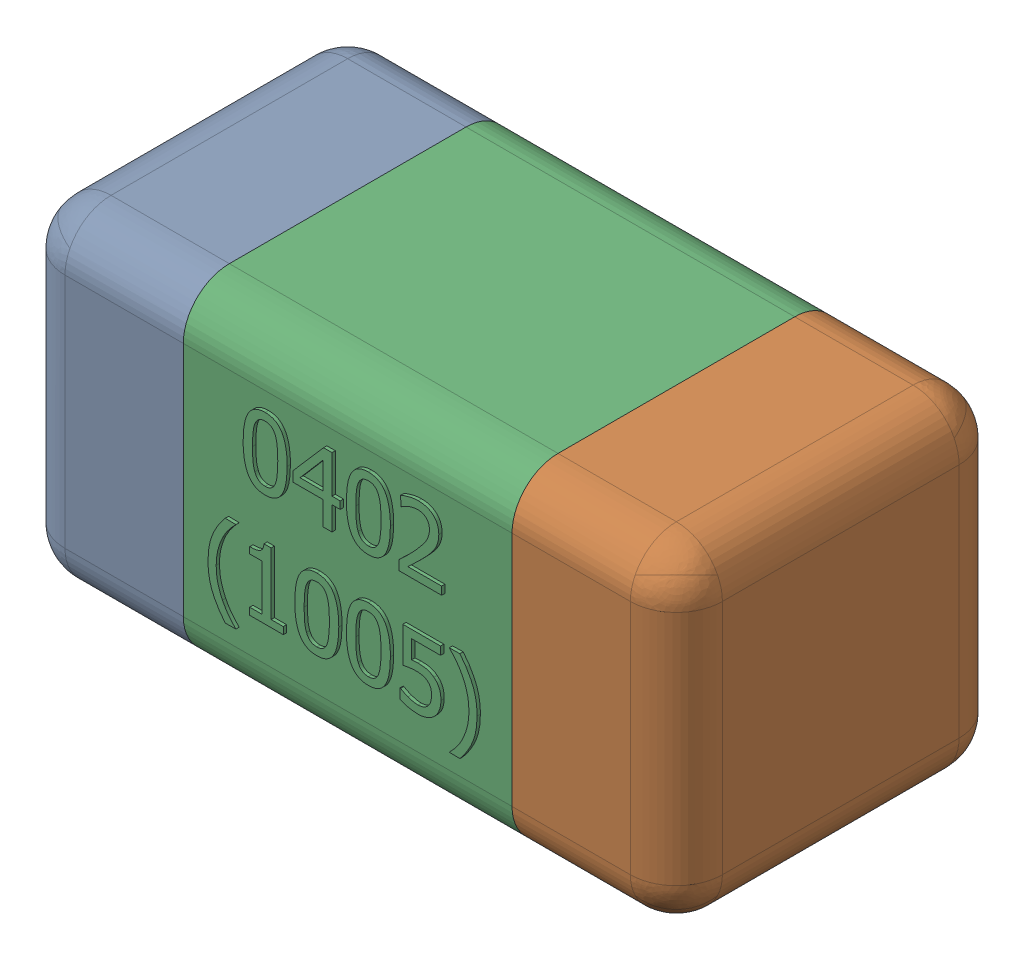
SolidWorks assembly C30, configuration Standard. Lengths in mm.
Overall size (1.01 0.51 0.51).
4 component instances, 3 part files, 0 mates.
Components (placement in the parent):
- C30-subassembly-1-1: C30-subassembly-1 [Standard] at (-15.0999 -10 0) x (1 0 0) z (0 0 1) size (1.01 0.51 0.51)
  - User Library-0402_Cap-1: User Library-0402_Cap [Standard] at origin size (0.26 0.51 0.51)
  - User Library-0402_Cap-1-1: User Library-0402_Cap-1 [Standard] at origin size (0.26 0.5 0.51)
  - User Library-0402_Cap-2-1: User Library-0402_Cap-2 [Standard] at origin size (0.5 0.5 0.51)
